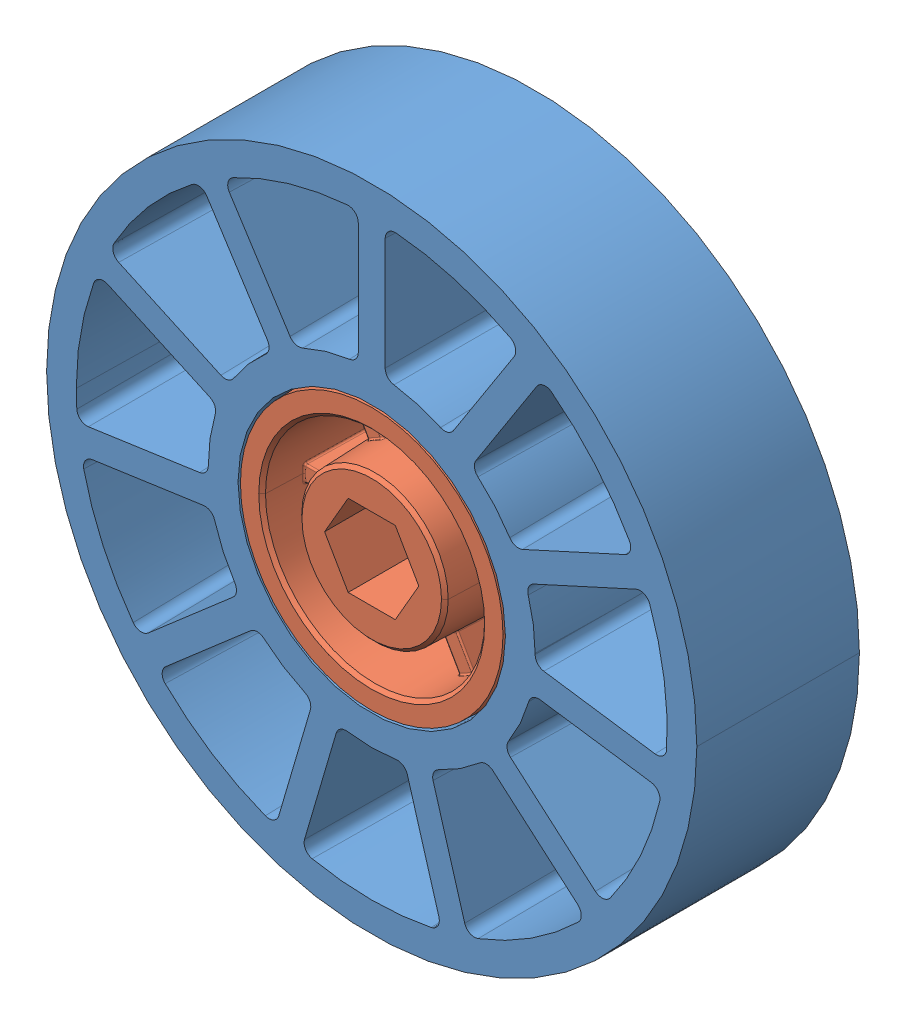
SolidWorks assembly am-3480 4IN 500Hex Bore Compliant Wheel, configuration Default. Lengths in mm.
Overall size (101.6 101.6 25.74).
3 component instances, 2 part files, 0 mates.
Components (placement in the parent):
- am-3480 4IN 500Hex Bore Compliant Wheel.STEP-1: am-3480 4IN 500Hex Bore Compliant Wheel.STEP [Default] at origin size (101.6 101.6 25.74)
  - 4IN Compliant Wheel FINAL Overmold.STEP-1: 4IN Compliant Wheel FINAL Overmold.STEP [Default] at (-16.2374 3.8509 18.652) size (101.6 101.6 25.74)
  - 2in Wheel Intergrated 0500 HEX Hub.STEP-1: 2in Wheel Intergrated 0500 HEX Hub.STEP [Default] at (-16.2374 3.8509 5.952) x (-1 0 0) z (0 0 -1) size (41.91 41.91 25.4)
